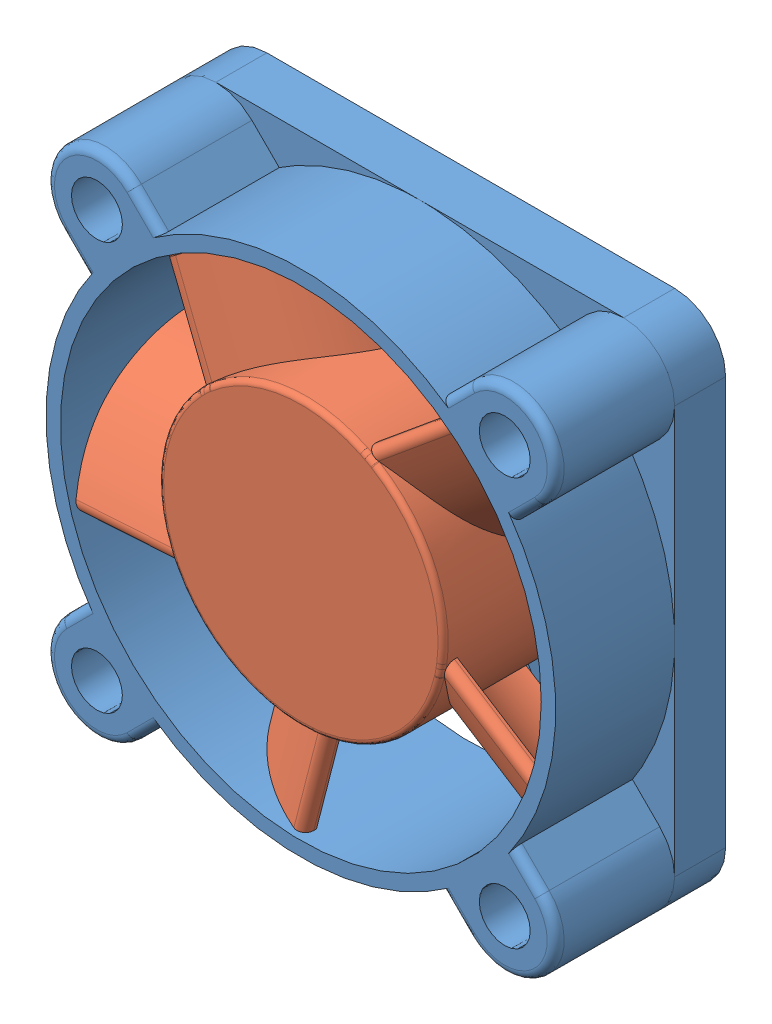
SolidWorks assembly Fan Assem, configuration Default. Lengths in mm.
Overall size (39.4 39.4 10.26).
2 component instances, 2 part files, 2 mates.
Components (placement in the parent):
- Fan Mount-1: Fan Mount [Default] at (12.866 15.0226 17.5776) size (30 30 10.03)
- Fan Blades-1: Fan Blades [Default] at (12.866 15.0226 23.5776) x (0.770588 0.637333 0) z (0 0 1) size (27.97 28 8.82)
Mates (geometry in assembly coordinates):
- Concentric1: concentric aligned: cylinder of Fan Mount-1 through (12.866 15.0226 19.0776) axis (0 0 -1) radius 0.75; cylinder of Fan Blades-1 through (12.866 15.0226 26.5776) axis (0 0 -1) radius 0.75
- Distance1: distance = 0.5 mm anti-aligned: plane of Fan Blades-1 through (12.866 15.0226 19.5776) normal (0 0 -1); plane of Fan Mount-1 through (12.866 15.0226 19.0776) normal (0 0 1)
